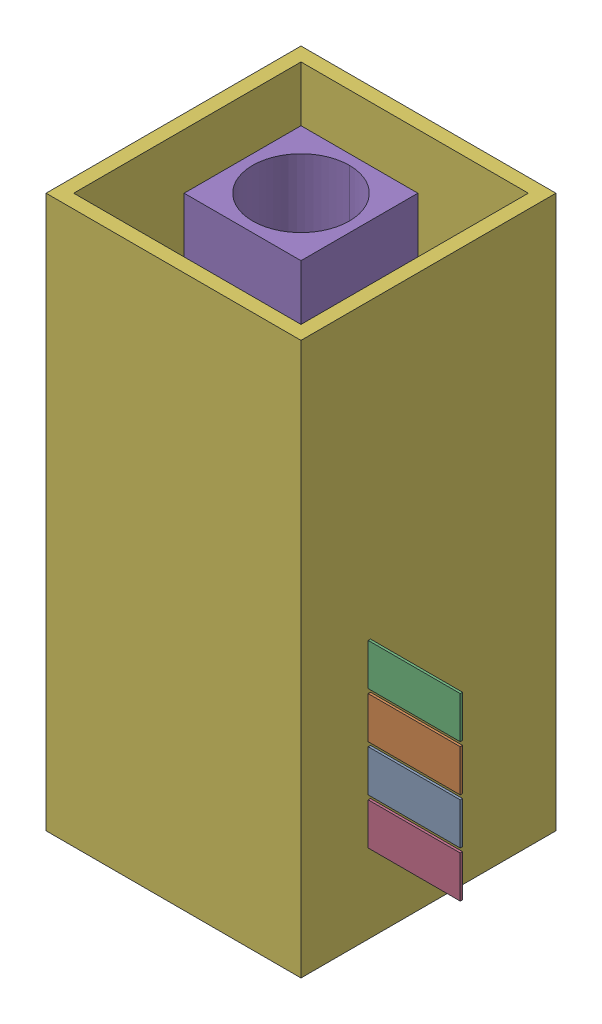
SolidWorks assembly piezo-drive, configuration Default. Lengths in mm.
Overall size (4.5 6 2.77).
17 component instances, 3 part files, 0 mates.
Components (placement in the parent):
- 6701982208-1: 6701982208 [Default] at (27.7 14.8 0) (suppressed, hidden)
- 6327400576-1: 6327400576 [Default] at (2.54 6.55 -0.1858) size (1 0.45 0.03)
  - 6701982208-1: 6701982208 [Default] at (27.7 14.8 0) (suppressed, hidden)
  - Extruded-25-1: Extruded-25 [Default] at origin size (1 0.45 0.03)
- 6327400576-2: 6327400576 [Default] at (2.54 7.05 -0.1858) size (1 0.45 0.03)
  - 6701982208-1: 6701982208 [Default] at (27.7 14.8 0) (suppressed, hidden)
  - Extruded-25-1: Extruded-25 [Default] at origin size (1 0.45 0.03)
- 6327400576-3: 6327400576 [Default] at (2.54 7.55 -0.1858) size (1 0.45 0.03)
  - 6701982208-1: 6701982208 [Default] at (27.7 14.8 0) (suppressed, hidden)
  - Extruded-25-1: Extruded-25 [Default] at origin size (1 0.45 0.03)
- 6327400576-4: 6327400576 [Default] at (2.54 6.0499 -0.1858) size (1 0.45 0.03)
  - 6701982208-1: 6701982208 [Default] at (27.7 14.8 0) (suppressed, hidden)
  - Extruded-25-1: Extruded-25 [Default] at origin size (1 0.45 0.03)
- piezo-drive-subassembly-1-1: piezo-drive-subassembly-1 [Default] at (-0.0751 10.2351 -1.5454) x (1 0 0) z (0 0 -1) size (2.77 6 2.77)
  - 6701982208-1: 6701982208 [Default] at (27.7 14.8 0) (suppressed, hidden)
  - sql-rv-1.8-6-12_nc-1: sql-rv-1.8-6-12_nc [Default] at origin size (1.27 6 1.27)
  - sql-rv-1.8-6-12_nc-1-1: sql-rv-1.8-6-12_nc-1 [Default] at origin size (2.77 6 2.77)
